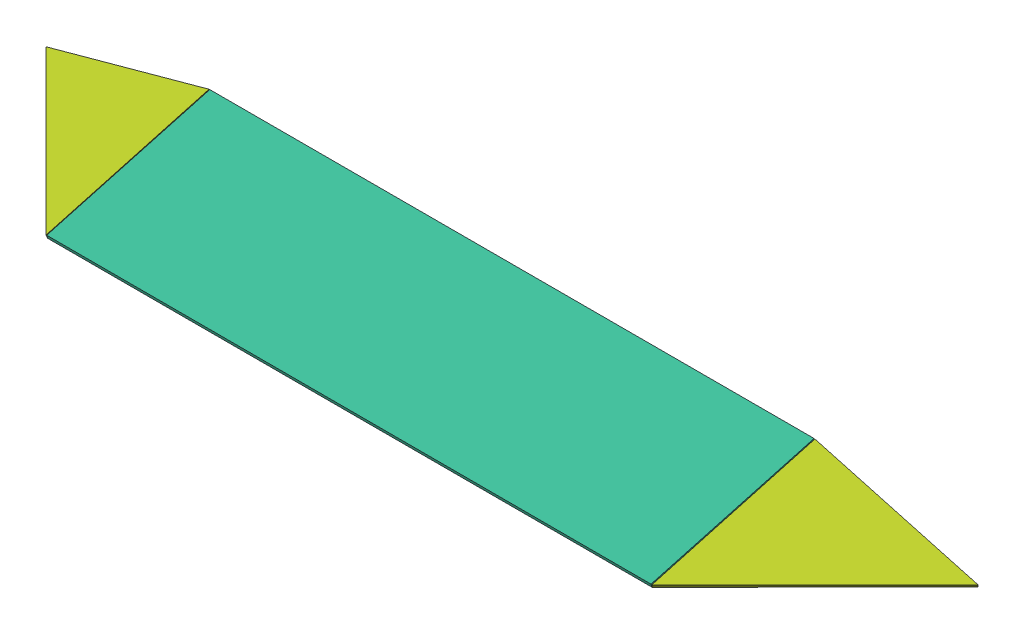
SolidWorks assembly GE-18127, configuration Default. Lengths in mm.
Overall size (945.08 57.7 248.9).
10 component instances, 7 part files, 30 mates.
Components (placement in the parent):
- GE-18127-01-1: GE-18127-01 [Default] at origin size (760.19 6.35 88.9)
- GE-18127-02-1: GE-18127-02 [Default] x (0 0 1) z (-1 0 0) size (28.57 25.85 609.6)
- GE-18127-03-1: GE-18127-03 [Default] at (0 32.2001 0) x (0 -0.263873 0.964557) z (-1 0 0) size (157.18 12.7 609.6)
- GE-18127-04-1: GE-18127-04 [Default] at (-284.5944 6.35 42.6562) x (-0.707107 0 0.707107) z (-0.707107 0 -0.707107) size (28.57 19.56 88.9)
- GE-18127-05-1: GE-18127-05 [Default] at (-304.8 32.2001 0) x (-0.659107 -0.361989 0.659198) z (-0.707149 -0.000023 -0.707064) size (114.3 12.7 213.17)
- GE-18127-04-2: GE-18127-04 [Default] at (347.4562 6.35 -20.2056) x (0.707107 0 0.707107) z (-0.707107 0 0.707107) size (28.57 19.56 88.9)
- GE-18127-05-2: GE-18127-05 [Default] at (304.8 32.2001 0) x (0.659107 -0.361989 0.659198) z (-0.707149 0.000023 0.707064) size (114.3 12.7 213.17)
- GE-18127-06-1: GE-18127-06 [Default] at (0 0.1257 165.3734) x (0 0.263873 -0.964557) z (0 -0.964557 -0.263873) size (171.45 612.77 3.17)
- GE-18127-07-1: GE-18127-07 [Default] at (-306.3875 45.3668 0) x (-0.65915 -0.361832 0.659241) z (-0.707149 -0.000023 -0.707064) size (125.39 3.17 233.86)
- GE-18127-07-2: GE-18127-07 [Default] at (306.3875 45.3668 0) x (0.659298 -0.361832 0.659093) z (-0.707011 -0.000053 0.707203) size (125.39 3.17 233.86)
Mates (geometry in assembly coordinates):
- Coincident1: coincident anti-aligned: plane of GE-18127-01-1 through (0 6.35 0) normal (0 1 0); plane of GE-18127-02-1 through (-304.8 6.35 0) normal (0 -1 0)
- Coincident2: coincident aligned: plane of GE-18127-01-1 through (0 6.35 0) normal (0 0 -1); plane of GE-18127-02-1 through (-304.8 0 0) normal (0 0 -1)
- Coincident3: coincident anti-aligned: plane of GE-18127-02-1 through (0 0 0) normal (-1 0 0); plane of assembly through (0 0 0) normal (1 0 0)
- Coincident4: coincident aligned: plane of GE-18127-01-1 through (0 0 0) normal (0 1 0); plane of assembly through (0 0 0) normal (0 1 0)
- Coincident5: coincident aligned: plane of GE-18127-01-1 through (0 0 0) normal (0 0 1); plane of assembly through (0 0 0) normal (0 0 1)
- Coincident6: coincident aligned: plane of GE-18127-01-1 through (0 0 0) normal (1 0 0); plane of assembly through (0 0 0) normal (1 0 0)
- Coincident7: coincident anti-aligned: plane of GE-18127-02-1 through (-304.8 29.9581 8.1956) normal (0 0.964557 0.263873); plane of GE-18127-03-1 through (-304.8 0.1059 117.3166) normal (0 -0.964557 -0.263873)
- Coincident8: coincident aligned: line of GE-18127-02-1 through (-304.8 32.2001 0) axis (1 0 0); line of GE-18127-03-1 through (-304.8 32.2001 0) axis (1 0 0)
- Coincident9: coincident aligned: plane of GE-18127-02-1 through (-304.8 0 0) normal (-1 0 0); plane of GE-18127-03-1 through (-304.8 32.2001 0) normal (-1 0 0)
- Coincident10: coincident anti-aligned: plane of GE-18127-01-1 through (0 6.35 0) normal (0 1 0); plane of GE-18127-04-1 through (-367.6618 6.35 0) normal (0 -1 0)
- Coincident12: coincident aligned: plane of GE-18127-01-1 through (0 6.35 0) normal (0 0 -1); plane of GE-18127-04-1 through (-367.6618 6.35 0) normal (0 0 -1)
- Coincident13: coincident anti-aligned: plane of GE-18127-02-1 through (-304.8 0 0) normal (-1 0 0); plane of GE-18127-04-1 through (-304.8 6.35 22.4506) normal (1 0 0)
- Coincident17: coincident: point of GE-18127-03-1; point of GE-18127-05-1
- Coincident18: coincident: line of GE-18127-04-1 through (-367.6618 14.9391 0) axis (0.707107 0 0.707107); plane of GE-18127-05-1 through (-470.6568 0.2943 -49.6613) normal (0.255965 -0.932182 -0.255965)
- Coincident19: coincident: point of GE-18127-03-1; plane of GE-18127-05-1 through (-308.001 -12.1618 207.9739) normal (0.966686 0.246893 0.067542)
- Coincident20: coincident anti-aligned: plane of GE-18127-01-1 through (0 6.35 0) normal (0 1 0); plane of GE-18127-04-2 through (304.8 6.35 62.8618) normal (0 -1 0)
- Coincident21: coincident aligned: plane of GE-18127-01-1 through (0 6.35 0) normal (0 0 -1); plane of GE-18127-04-2 through (327.2506 6.35 0) normal (0 0 -1)
- Coincident22: coincident anti-aligned: plane of GE-18127-02-1 through (304.8 0 0) normal (1 0 0); plane of GE-18127-04-2 through (304.8 6.35 62.8618) normal (-1 0 0)
- Coincident23: coincident: point of GE-18127-03-1; point of GE-18127-05-2
- Coincident24: coincident: line of GE-18127-04-2 through (304.8 14.9391 62.8618) axis (0.707107 0 -0.707107); plane of GE-18127-05-2 through (255.1177 0.3014 165.8519) normal (-0.255965 -0.932182 -0.255965)
- Coincident25: coincident: point of GE-18127-03-1; plane of GE-18127-05-2 through (308.0508 44.0388 3.2508) normal (-0.966686 0.246893 0.067542)
- Coincident26: coincident anti-aligned: plane of GE-18127-03-1 through (-304.8 44.45 3.3512) normal (0 0.964557 0.263873); plane of GE-18127-06-1 through (306.3875 0.1257 165.3734) normal (0 -0.964557 -0.263873)
- Coincident27: coincident aligned: plane of GE-18127-06-1 through (0 0.1257 165.3734) normal (1 0 0); plane of assembly through (0 0 0) normal (1 0 0)
- Coincident28: coincident: plane of GE-18127-02-1 through (-304.8 0 0) normal (0 0 -1); line of GE-18127-06-1 through (612.775 306.3875 45.3668) axis (0 -1 0)
- Coincident29: coincident: point of GE-18127-06-1; point of GE-18127-07-1
- Coincident30: coincident: line of GE-18127-05-1 through (-458.7592 2.661 3.2336) axis (0.707149 0.000023 0.707064); plane of GE-18127-07-1 through (-306.3875 45.3668 0) normal (0.255854 -0.932243 -0.255854)
- Coincident31: coincident: point of GE-18127-06-1; plane of GE-18127-07-1 through (-307.1998 48.3267 0.8123) normal (0.966715 0.246786 0.067513)
- Coincident32: coincident: point of GE-18127-06-1; point of GE-18127-07-2
- Coincident33: coincident: line of GE-18127-05-2 through (308.0141 2.6659 153.9606) axis (0.707149 -0.000023 -0.707064); plane of GE-18127-07-2 through (306.3875 45.3668 0) normal (-0.255854 -0.932243 -0.255854)
- Coincident34: coincident: plane of GE-18127-06-1 through (306.3875 0.1257 165.3734) normal (1 0 0); point of GE-18127-07-2
